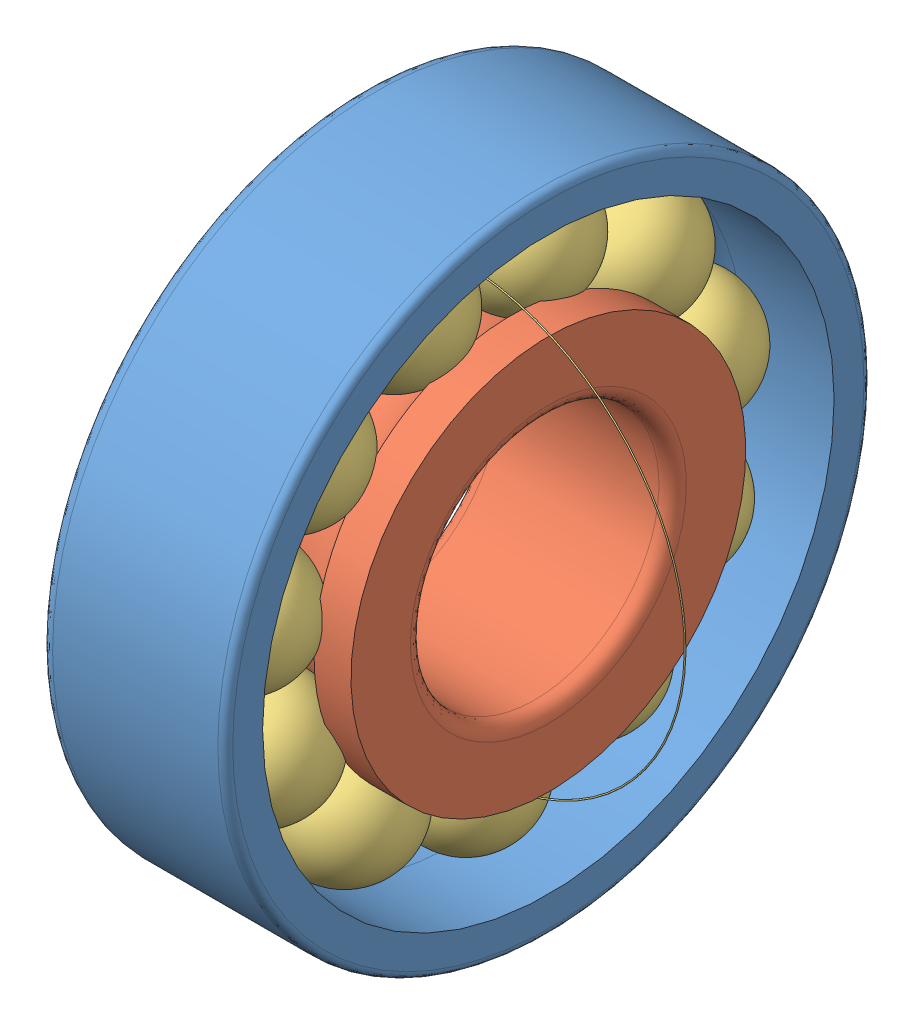
SolidWorks assembly Elemento 3 Rodamiento 7304, configuration Predeterminado. Lengths in mm.
Overall size (36.1 52 52).
3 component instances, 3 part files, 4 mates.
Components (placement in the parent):
- rodamiento_-_7304_be_1_01-1: rodamiento_-_7304_be_1_01 [Default] at origin size (15 52 52)
- rodamiento_-_7304_be_1_02-1: rodamiento_-_7304_be_1_02 [Default] x (1 0 0) z (0 0.085608 0.996329) size (15 31.77 31.77)
- Bolas rofamiento-1: Bolas rofamiento [Predeterminado] at (8 0 0) x (1 0 0) z (0 0.020733 -0.999785) size (36.1 45.27 45.63)
Mates (geometry in assembly coordinates):
- Concéntrica1: concentric aligned: cylinder of rodamiento_-_7304_be_1_01-1 through (1.1 0 0) axis (-1 0 0) radius 26; cylinder of rodamiento_-_7304_be_1_02-1 through (13.9 0 0) axis (-1 0 0) radius 13
- Coincidente1: coincident aligned: plane of rodamiento_-_7304_be_1_01-1 through (15 25.4 0) normal (1 0 0); plane of rodamiento_-_7304_be_1_02-1 through (15 11.0593 -0.9502) normal (1 0 0)
- Concéntrica2: concentric anti-aligned: cylinder of rodamiento_-_7304_be_1_01-1 through (1.1 0 0) axis (-1 0 0) radius 26; circle of Bolas rofamiento-1
- Distancia1: distance = 7 mm aligned: plane of Bolas rofamiento-1 through (8 0 0) normal (1 0 0); plane of rodamiento_-_7304_be_1_02-1 through (15 11.0593 -0.9502) normal (1 0 0)
